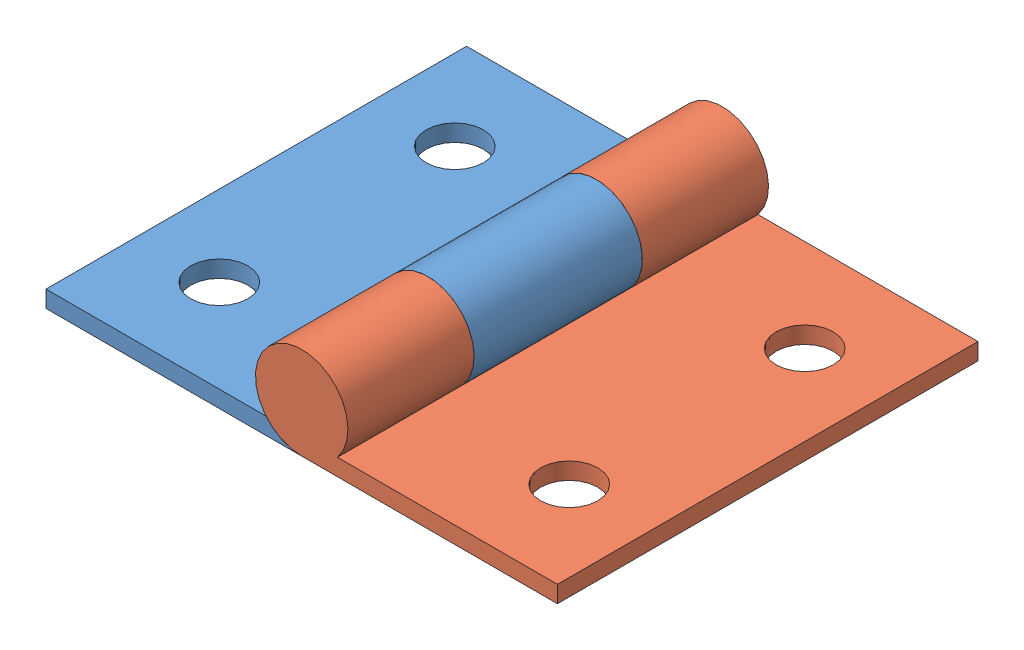
SolidWorks assembly 合页, configuration 默认. Lengths in mm.
Overall size (30.4 5.5 25).
2 component instances, 2 part files, 3 mates.
Components (placement in the parent):
- 合页另一半-1: 合页另一半 [默认] at (5.6459 -0.3898 12.5) size (17.95 5.5 25)
- 合页一半-1: 合页一半 [默认] at (5.6459 -0.3898 37.5) x (-1 0 0) z (0 0 -1) size (17.95 5.5 25)
Mates (geometry in assembly coordinates):
- 重合1: coincident: plane of 合页另一半-1 through (5.6459 -0.3898 30) normal (0 0 1); plane of 合页一半-1 through (5.6459 -0.3898 30) normal (0 0 -1)
- 同心1: concentric: cylinder of 合页另一半-1 through (5.6459 -0.3898 37.5) axis (0 0 -1) radius 2.75; cylinder of 合页一半-1 through (5.6459 -0.3898 12.5) axis (0 0 1) radius 2.75
- 重合2: coincident aligned: plane of 合页另一半-1 through (5.6459 -3.1398 37.5) normal (0 -1 0); plane of 合页一半-1 through (5.6459 -3.1398 12.5) normal (0 -1 0)
